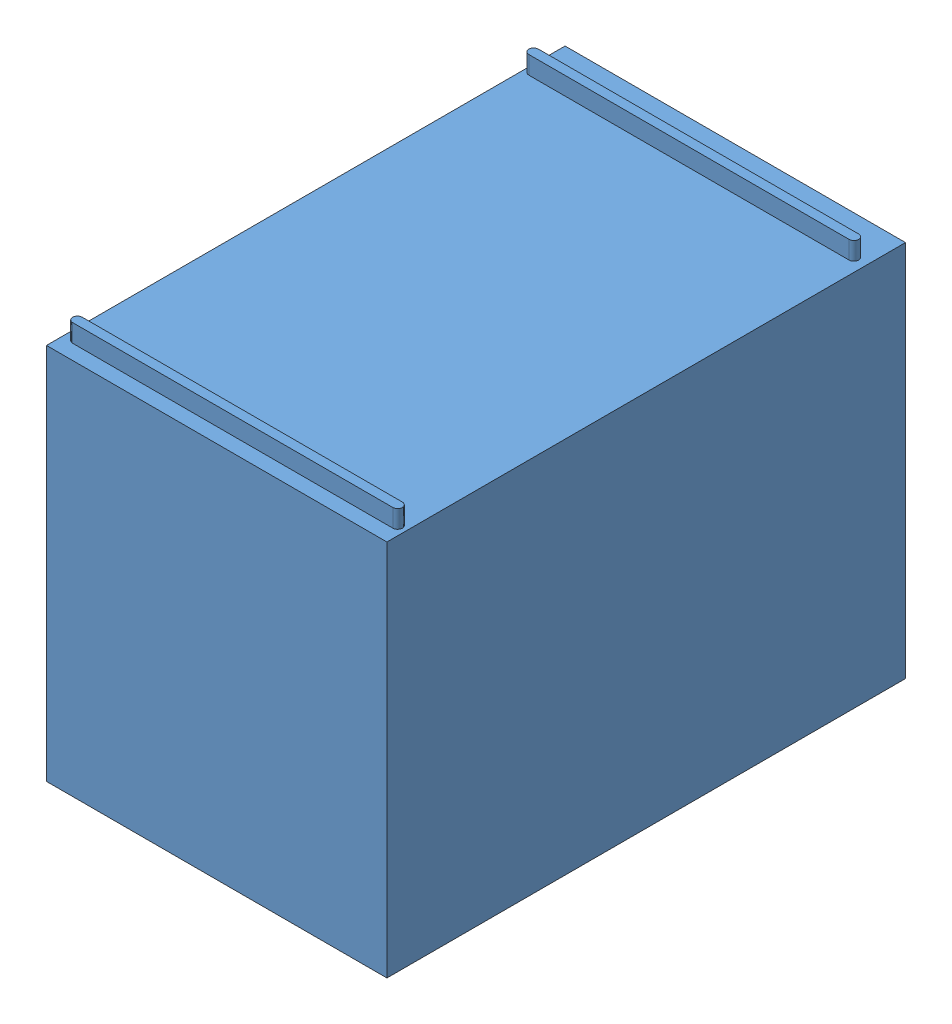
SolidWorks assembly ANA_GÖVDE, configuration Default. Lengths in mm.
Overall size (57 66.22 86.83).
200 component instances, 72 part files, 0 mates.
Components (placement in the parent):
- GÖVDE-1: GÖVDE [Default] at (-12.1036 34.1055 2.4795) size (57 66.22 86.83)
- ArduinoUno_CH340_USBC.step-1: ArduinoUno_CH340_USBC.step [Default] at (-8.7017 80.6973 66.2252) x (-0.00918 -0.026173 -0.999615) z (-0.017217 -0.999505 0.026328) size (73.95 53.67 14.6)
  - USB_C_Receptacle_16P_TopMnt_Horizontal_GCT_USB4105-xx-A036.step-1: USB_C_Receptacle_16P_TopMnt_Horizontal_GCT_USB4105-xx-A036.step [Default] at (-29.25 35.05 0) x (0 -1 0) z (0 0 1) size (8.94 7.78 4.26)
    - USB_C_Receptacle_16P_TopMnt_Horizontal_GCT_USB4105-xx-A.step-1: USB_C_Receptacle_16P_TopMnt_Horizontal_GCT_USB4105-xx-A.step [Default] at origin size (0.25 2.4 0.1)
    - USB_C_Receptacle_16P_TopMnt_Horizontal_GCT_USB4105-xx-A001.step-1: USB_C_Receptacle_16P_TopMnt_Horizontal_GCT_USB4105-xx-A001.step [Default] at origin size (0.25 2.4 0.1)
    - USB_C_Receptacle_16P_TopMnt_Horizontal_GCT_USB4105-xx-A002.step-1: USB_C_Receptacle_16P_TopMnt_Horizontal_GCT_USB4105-xx-A002.step [Default] at origin size (0.25 1.9 0.1)
    - USB_C_Receptacle_16P_TopMnt_Horizontal_GCT_USB4105-xx-A003.step-1: USB_C_Receptacle_16P_TopMnt_Horizontal_GCT_USB4105-xx-A003.step [Default] at origin size (0.25 1.9 0.1)
    - USB_C_Receptacle_16P_TopMnt_Horizontal_GCT_USB4105-xx-A004.step-1: USB_C_Receptacle_16P_TopMnt_Horizontal_GCT_USB4105-xx-A004.step [Default] at origin size (0.25 2.4 0.1)
    - USB_C_Receptacle_16P_TopMnt_Horizontal_GCT_USB4105-xx-A005.step-1: USB_C_Receptacle_16P_TopMnt_Horizontal_GCT_USB4105-xx-A005.step [Default] at origin size (0.25 2.4 0.1)
    - USB_C_Receptacle_16P_TopMnt_Horizontal_GCT_USB4105-xx-A006.step-1: USB_C_Receptacle_16P_TopMnt_Horizontal_GCT_USB4105-xx-A006.step [Default] at origin size (0.25 1.9 0.1)
    - USB_C_Receptacle_16P_TopMnt_Horizontal_GCT_USB4105-xx-A007.step-1: USB_C_Receptacle_16P_TopMnt_Horizontal_GCT_USB4105-xx-A007.step [Default] at origin size (0.25 1.9 0.1)
    - USB_C_Receptacle_16P_TopMnt_Horizontal_GCT_USB4105-xx-A008.step-1: USB_C_Receptacle_16P_TopMnt_Horizontal_GCT_USB4105-xx-A008.step [Default] at origin size (4.45 7.05 3.59)
    - USB_C_Receptacle_16P_TopMnt_Horizontal_GCT_USB4105-xx-A009.step-1: USB_C_Receptacle_16P_TopMnt_Horizontal_GCT_USB4105-xx-A009.step [Default] at origin size (0.2 0.8 0.12)
    - USB_C_Receptacle_16P_TopMnt_Horizontal_GCT_USB4105-xx-A010.step-1: USB_C_Receptacle_16P_TopMnt_Horizontal_GCT_USB4105-xx-A010.step [Default] at origin size (0.2 0.8 0.12)
    - USB_C_Receptacle_16P_TopMnt_Horizontal_GCT_USB4105-xx-A011.step-1: USB_C_Receptacle_16P_TopMnt_Horizontal_GCT_USB4105-xx-A011.step [Default] at origin size (0.2 0.8 0.12)
    - USB_C_Receptacle_16P_TopMnt_Horizontal_GCT_USB4105-xx-A012.step-1: USB_C_Receptacle_16P_TopMnt_Horizontal_GCT_USB4105-xx-A012.step [Default] at origin size (0.2 0.8 0.12)
    - USB_C_Receptacle_16P_TopMnt_Horizontal_GCT_USB4105-xx-A013.step-1: USB_C_Receptacle_16P_TopMnt_Horizontal_GCT_USB4105-xx-A013.step [Default] at origin size (0.2 0.8 0.12)
    - USB_C_Receptacle_16P_TopMnt_Horizontal_GCT_USB4105-xx-A014.step-1: USB_C_Receptacle_16P_TopMnt_Horizontal_GCT_USB4105-xx-A014.step [Default] at origin size (0.2 0.8 0.12)
    - USB_C_Receptacle_16P_TopMnt_Horizontal_GCT_USB4105-xx-A015.step-1: USB_C_Receptacle_16P_TopMnt_Horizontal_GCT_USB4105-xx-A015.step [Default] at origin size (0.2 0.8 0.12)
    - USB_C_Receptacle_16P_TopMnt_Horizontal_GCT_USB4105-xx-A016.step-1: USB_C_Receptacle_16P_TopMnt_Horizontal_GCT_USB4105-xx-A016.step [Default] at origin size (0.2 0.8 0.12)
    - USB_C_Receptacle_16P_TopMnt_Horizontal_GCT_USB4105-xx-A017.step-1: USB_C_Receptacle_16P_TopMnt_Horizontal_GCT_USB4105-xx-A017.step [Default] at origin size (4.47 7.33 4.26)
    - USB_C_Receptacle_16P_TopMnt_Horizontal_GCT_USB4105-xx-A018.step-1: USB_C_Receptacle_16P_TopMnt_Horizontal_GCT_USB4105-xx-A018.step [Default] at origin size (0.25 2.4 0.1)
    - USB_C_Receptacle_16P_TopMnt_Horizontal_GCT_USB4105-xx-A019.step-1: USB_C_Receptacle_16P_TopMnt_Horizontal_GCT_USB4105-xx-A019.step [Default] at origin size (0.25 2.4 0.1)
    - USB_C_Receptacle_16P_TopMnt_Horizontal_GCT_USB4105-xx-A020.step-1: USB_C_Receptacle_16P_TopMnt_Horizontal_GCT_USB4105-xx-A020.step [Default] at origin size (0.25 1.9 0.1)
    - USB_C_Receptacle_16P_TopMnt_Horizontal_GCT_USB4105-xx-A021.step-1: USB_C_Receptacle_16P_TopMnt_Horizontal_GCT_USB4105-xx-A021.step [Default] at origin size (0.25 1.9 0.1)
    - USB_C_Receptacle_16P_TopMnt_Horizontal_GCT_USB4105-xx-A022.step-1: USB_C_Receptacle_16P_TopMnt_Horizontal_GCT_USB4105-xx-A022.step [Default] at origin size (0.25 2.4 0.1)
    - USB_C_Receptacle_16P_TopMnt_Horizontal_GCT_USB4105-xx-A023.step-1: USB_C_Receptacle_16P_TopMnt_Horizontal_GCT_USB4105-xx-A023.step [Default] at origin size (0.25 2.4 0.1)
    - USB_C_Receptacle_16P_TopMnt_Horizontal_GCT_USB4105-xx-A024.step-1: USB_C_Receptacle_16P_TopMnt_Horizontal_GCT_USB4105-xx-A024.step [Default] at origin size (0.25 1.9 0.1)
    - USB_C_Receptacle_16P_TopMnt_Horizontal_GCT_USB4105-xx-A025.step-1: USB_C_Receptacle_16P_TopMnt_Horizontal_GCT_USB4105-xx-A025.step [Default] at origin size (0.25 1.9 0.1)
    - USB_C_Receptacle_16P_TopMnt_Horizontal_GCT_USB4105-xx-A026.step-1: USB_C_Receptacle_16P_TopMnt_Horizontal_GCT_USB4105-xx-A026.step [Default] at origin size (4.45 7.05 3.59)
    - USB_C_Receptacle_16P_TopMnt_Horizontal_GCT_USB4105-xx-A027.step-1: USB_C_Receptacle_16P_TopMnt_Horizontal_GCT_USB4105-xx-A027.step [Default] at origin size (0.2 0.8 0.12)
    - USB_C_Receptacle_16P_TopMnt_Horizontal_GCT_USB4105-xx-A028.step-1: USB_C_Receptacle_16P_TopMnt_Horizontal_GCT_USB4105-xx-A028.step [Default] at origin size (0.2 0.8 0.12)
    - USB_C_Receptacle_16P_TopMnt_Horizontal_GCT_USB4105-xx-A029.step-1: USB_C_Receptacle_16P_TopMnt_Horizontal_GCT_USB4105-xx-A029.step [Default] at origin size (0.2 0.8 0.12)
    - USB_C_Receptacle_16P_TopMnt_Horizontal_GCT_USB4105-xx-A030.step-1: USB_C_Receptacle_16P_TopMnt_Horizontal_GCT_USB4105-xx-A030.step [Default] at origin size (0.2 0.8 0.12)
    - USB_C_Receptacle_16P_TopMnt_Horizontal_GCT_USB4105-xx-A031.step-1: USB_C_Receptacle_16P_TopMnt_Horizontal_GCT_USB4105-xx-A031.step [Default] at origin size (0.2 0.8 0.12)
    - USB_C_Receptacle_16P_TopMnt_Horizontal_GCT_USB4105-xx-A032.step-1: USB_C_Receptacle_16P_TopMnt_Horizontal_GCT_USB4105-xx-A032.step [Default] at origin size (0.2 0.8 0.12)
    - USB_C_Receptacle_16P_TopMnt_Horizontal_GCT_USB4105-xx-A033.step-1: USB_C_Receptacle_16P_TopMnt_Horizontal_GCT_USB4105-xx-A033.step [Default] at origin size (0.2 0.8 0.12)
    - USB_C_Receptacle_16P_TopMnt_Horizontal_GCT_USB4105-xx-A034.step-1: USB_C_Receptacle_16P_TopMnt_Horizontal_GCT_USB4105-xx-A034.step [Default] at origin size (0.2 0.8 0.12)
    - USB_C_Receptacle_16P_TopMnt_Horizontal_GCT_USB4105-xx-A035.step-1: USB_C_Receptacle_16P_TopMnt_Horizontal_GCT_USB4105-xx-A035.step [Default] at origin size (4.47 7.33 4.26)
  - BarrelJack_Horizontal005.step-1: BarrelJack_Horizontal005.step [Default] at (-24.6 4.05 0) size (14.2 9.3 14.6)
    - BarrelJack_Horizontal.step-1: BarrelJack_Horizontal.step [Default] at origin size (13.7 9 10.8)
    - BarrelJack_Horizontal001.step-1: BarrelJack_Horizontal001.step [Default] at origin size (14.2 5.28 12.54)
    - BarrelJack_Horizontal002.step-1: BarrelJack_Horizontal002.step [Default] at origin size (10.5 5 3.6)
    - BarrelJack_Horizontal003.step-1: BarrelJack_Horizontal003.step [Default] at origin size (2 6.72 7.2)
    - BarrelJack_Horizontal004.step-1: BarrelJack_Horizontal004.step [Default] at origin size (0.2 2 3.8)
  - C_Elec_63x054_1.step-1: C_Elec_63x054_1.step [Default] at (-11.6 6.15 0) x (0 -1 0) z (0 0 1) size (8.61 8.6 5.4)
    - C_Elec_63x54.step-1: C_Elec_63x54.step [Default] at origin size (8.61 8.6 5.4)
    - C_Elec_63x055.step-1: C_Elec_63x055.step [Default] at origin size (0.02 0.02 0.01)
  - C_Elec_63x054_1.step-2: C_Elec_63x054_1.step [Default] at (-18.65 6.15 0) x (0 -1 0) z (0 0 1) size (8.61 8.6 5.4)
    - C_Elec_63x54.step-1: C_Elec_63x54.step [Default] at origin size (8.61 8.6 5.4)
    - C_Elec_63x055.step-1: C_Elec_63x055.step [Default] at origin size (0.02 0.02 0.01)
  - Resistors.step-1: Resistors.step [Default] at origin size (57.6 24.2 0.45)
    - R_0603_1608Metric.step-1: R_0603_1608Metric.step [Default] at (-30.35 41.6 0) size (1.6 0.8 0.45)
    - R_0603_1608Metric.step-2: R_0603_1608Metric.step [Default] at (-30.45 28.5 0) size (1.6 0.8 0.45)
    - R_0603_1608Metric.step-3: R_0603_1608Metric.step [Default] at (-30.15 24.3 0) size (1.6 0.8 0.45)
    - R_0603_1608Metric.step-4: R_0603_1608Metric.step [Default] at (-26.3 20.25 0) x (0 1 0) z (0 0 1) size (1.6 0.8 0.45)
    - R_0603_1608Metric.step-5: R_0603_1608Metric.step [Default] at (-23.85 20.3 0) x (0 1 0) z (0 0 1) size (1.6 0.8 0.45)
    - R_0603_1608Metric.step-6: R_0603_1608Metric.step [Default] at (-6.75 37.3 0) size (1.6 0.8 0.45)
    - R_0603_1608Metric.step-7: R_0603_1608Metric.step [Default] at (-6.8 35.35 0) size (1.6 0.8 0.45)
    - R_0603_1608Metric.step-8: R_0603_1608Metric.step [Default] at (-6.75 31 0) size (1.6 0.8 0.45)
    - R_0603_1608Metric.step-9: R_0603_1608Metric.step [Default] at (-6.8 28.85 0) size (1.6 0.8 0.45)
    - R_0603_1608Metric.step-10: R_0603_1608Metric.step [Default] at (-6.8 24.45 0) size (1.6 0.8 0.45)
    - R_0603_1608Metric.step-11: R_0603_1608Metric.step [Default] at (-6.85 18.2 0) size (1.6 0.8 0.45)
    - R_0603_1608Metric.step-12: R_0603_1608Metric.step [Default] at (23.75 26.5 0) x (0 1 0) z (0 0 1) size (1.6 0.8 0.45)
    - R_0603_1608Metric.step-13: R_0603_1608Metric.step [Default] at (25.95 25.65 0) x (0 1 0) z (0 0 1) size (1.6 0.8 0.45)
  - Capacitors.step-1: Capacitors.step [Default] at origin size (50.6 26.8 0.8)
    - C_0603_1608Metric.step-1: C_0603_1608Metric.step [Default] at (-20.2 39.55 0) size (1.6 0.8 0.8)
    - C_0603_1608Metric.step-2: C_0603_1608Metric.step [Default] at (-16.1 39.55 0) size (1.6 0.8 0.8)
    - C_0603_1608Metric.step-3: C_0603_1608Metric.step [Default] at (-11.95 39.55 0) size (1.6 0.8 0.8)
    - C_0603_1608Metric.step-4: C_0603_1608Metric.step [Default] at (-25.6 26.45 0) size (1.6 0.8 0.8)
    - C_0603_1608Metric.step-5: C_0603_1608Metric.step [Default] at (-25.65 24.35 0) size (1.6 0.8 0.8)
    - C_0603_1608Metric.step-6: C_0603_1608Metric.step [Default] at (-6.85 22.4 0) size (1.6 0.8 0.8)
    - C_0603_1608Metric.step-7: C_0603_1608Metric.step [Default] at (-17.65 17.95 0) size (1.6 0.8 0.8)
    - C_0603_1608Metric.step-8: C_0603_1608Metric.step [Default] at (-11.9 18 0) size (1.6 0.8 0.8)
    - C_0603_1608Metric.step-9: C_0603_1608Metric.step [Default] at (-22.85 14 0) x (0 1 0) z (0 0 1) size (1.6 0.8 0.8)
    - C_0603_1608Metric.step-10: C_0603_1608Metric.step [Default] at (-15.6 13.95 0) x (0 1 0) z (0 0 1) size (1.6 0.8 0.8)
    - C_0603_1608Metric.step-11: C_0603_1608Metric.step [Default] at (23.75 30.55 0) x (0 1 0) z (0 0 1) size (1.6 0.8 0.8)
    - C_0603_1608Metric.step-12: C_0603_1608Metric.step [Default] at (23.75 22.5 0) x (0 1 0) z (0 0 1) size (1.6 0.8 0.8)
  - Array.step-1: Array.step [Default] at origin size (19.58 4.34 1.7)
    - trou001.step-1: trou001.step [Default] at (-5.08 0 0) size (1.8 1.8 1.7)
    - trou001.step-2: trou001.step [Default] at (-5.08 2.54 0) size (1.8 1.8 1.7)
    - trou001.step-3: trou001.step [Default] at (-2.54 0 0) size (1.8 1.8 1.7)
    - trou001.step-4: trou001.step [Default] at (-2.54 2.54 0) size (1.8 1.8 1.7)
    - trou001.step-5: trou001.step [Default] at origin size (1.8 1.8 1.7)
    - trou001.step-6: trou001.step [Default] at (0 2.54 0) size (1.8 1.8 1.7)
    - trou001.step-7: trou001.step [Default] at (2.54 0 0) size (1.8 1.8 1.7)
    - trou001.step-8: trou001.step [Default] at (2.54 2.54 0) size (1.8 1.8 1.7)
    - trou001.step-9: trou001.step [Default] at (5.08 0 0) size (1.8 1.8 1.7)
    - trou001.step-10: trou001.step [Default] at (5.08 2.54 0) size (1.8 1.8 1.7)
    - trou001.step-11: trou001.step [Default] at (7.62 0 0) size (1.8 1.8 1.7)
    - trou001.step-12: trou001.step [Default] at (7.62 2.54 0) size (1.8 1.8 1.7)
    - trou001.step-13: trou001.step [Default] at (10.16 0 0) size (1.8 1.8 1.7)
    - trou001.step-14: trou001.step [Default] at (10.16 2.54 0) size (1.8 1.8 1.7)
    - trou001.step-15: trou001.step [Default] at (12.7 0 0) size (1.8 1.8 1.7)
    - trou001.step-16: trou001.step [Default] at (12.7 2.54 0) size (1.8 1.8 1.7)
  - Array001.step-1: Array001.step [Default] at origin size (14.5 4.34 1.7)
    - trou002.step-1: trou002.step [Default] at (17.78 0 0) size (1.8 1.8 1.7)
    - trou002.step-2: trou002.step [Default] at (17.78 2.54 0) size (1.8 1.8 1.7)
    - trou002.step-3: trou002.step [Default] at (20.32 0 0) size (1.8 1.8 1.7)
    - trou002.step-4: trou002.step [Default] at (20.32 2.54 0) size (1.8 1.8 1.7)
    - trou002.step-5: trou002.step [Default] at (22.86 0 0) size (1.8 1.8 1.7)
    - trou002.step-6: trou002.step [Default] at (22.86 2.54 0) size (1.8 1.8 1.7)
    - trou002.step-7: trou002.step [Default] at (25.4 0 0) size (1.8 1.8 1.7)
    - trou002.step-8: trou002.step [Default] at (25.4 2.54 0) size (1.8 1.8 1.7)
    - trou002.step-9: trou002.step [Default] at (27.94 0 0) size (1.8 1.8 1.7)
    - trou002.step-10: trou002.step [Default] at (27.94 2.54 0) size (1.8 1.8 1.7)
    - trou002.step-11: trou002.step [Default] at (30.48 0 0) size (1.8 1.8 1.7)
    - trou002.step-12: trou002.step [Default] at (30.48 2.54 0) size (1.8 1.8 1.7)
  - Array002.step-1: Array002.step [Default] at origin size (24.66 4.34 1.7)
    - trou003.step-1: trou003.step [Default] at (-13.97 45.72 0) size (1.8 1.8 1.7)
    - trou003.step-2: trou003.step [Default] at (-13.97 48.26 0) size (1.8 1.8 1.7)
    - trou003.step-3: trou003.step [Default] at (-11.43 45.72 0) size (1.8 1.8 1.7)
    - trou003.step-4: trou003.step [Default] at (-11.43 48.26 0) size (1.8 1.8 1.7)
    - trou003.step-5: trou003.step [Default] at (-8.89 45.72 0) size (1.8 1.8 1.7)
    - trou003.step-6: trou003.step [Default] at (-8.89 48.26 0) size (1.8 1.8 1.7)
    - trou003.step-7: trou003.step [Default] at (-6.35 45.72 0) size (1.8 1.8 1.7)
    - trou003.step-8: trou003.step [Default] at (-6.35 48.26 0) size (1.8 1.8 1.7)
    - trou003.step-9: trou003.step [Default] at (-3.81 45.72 0) size (1.8 1.8 1.7)
    - trou003.step-10: trou003.step [Default] at (-3.81 48.26 0) size (1.8 1.8 1.7)
    - trou003.step-11: trou003.step [Default] at (-1.27 45.72 0) size (1.8 1.8 1.7)
    - trou003.step-12: trou003.step [Default] at (-1.27 48.26 0) size (1.8 1.8 1.7)
    - trou003.step-13: trou003.step [Default] at (1.27 45.72 0) size (1.8 1.8 1.7)
    - trou003.step-14: trou003.step [Default] at (1.27 48.26 0) size (1.8 1.8 1.7)
    - trou003.step-15: trou003.step [Default] at (3.81 45.72 0) size (1.8 1.8 1.7)
    - trou003.step-16: trou003.step [Default] at (3.81 48.26 0) size (1.8 1.8 1.7)
    - trou003.step-17: trou003.step [Default] at (6.35 45.72 0) size (1.8 1.8 1.7)
    - trou003.step-18: trou003.step [Default] at (6.35 48.26 0) size (1.8 1.8 1.7)
    - trou003.step-19: trou003.step [Default] at (8.89 45.72 0) size (1.8 1.8 1.7)
    - trou003.step-20: trou003.step [Default] at (8.89 48.26 0) size (1.8 1.8 1.7)
  - Array003.step-1: Array003.step [Default] at origin size (19.58 4.34 1.7)
    - trou004.step-1: trou004.step [Default] at (12.7 45.72 0) size (1.8 1.8 1.7)
    - trou004.step-2: trou004.step [Default] at (12.7 48.26 0) size (1.8 1.8 1.7)
    - trou004.step-3: trou004.step [Default] at (15.24 45.72 0) size (1.8 1.8 1.7)
    - trou004.step-4: trou004.step [Default] at (15.24 48.26 0) size (1.8 1.8 1.7)
    - trou004.step-5: trou004.step [Default] at (17.78 45.72 0) size (1.8 1.8 1.7)
    - trou004.step-6: trou004.step [Default] at (17.78 48.26 0) size (1.8 1.8 1.7)
    - trou004.step-7: trou004.step [Default] at (20.32 45.72 0) size (1.8 1.8 1.7)
    - trou004.step-8: trou004.step [Default] at (20.32 48.26 0) size (1.8 1.8 1.7)
    - trou004.step-9: trou004.step [Default] at (22.86 45.72 0) size (1.8 1.8 1.7)
    - trou004.step-10: trou004.step [Default] at (22.86 48.26 0) size (1.8 1.8 1.7)
    - trou004.step-11: trou004.step [Default] at (25.4 45.72 0) size (1.8 1.8 1.7)
    - trou004.step-12: trou004.step [Default] at (25.4 48.26 0) size (1.8 1.8 1.7)
    - trou004.step-13: trou004.step [Default] at (27.94 45.72 0) size (1.8 1.8 1.7)
    - trou004.step-14: trou004.step [Default] at (27.94 48.26 0) size (1.8 1.8 1.7)
    - trou004.step-15: trou004.step [Default] at (30.48 45.72 0) size (1.8 1.8 1.7)
    - trou004.step-16: trou004.step [Default] at (30.48 48.26 0) size (1.8 1.8 1.7)
  - Array004.step-1: Array004.step [Default] at origin size (4.34 6.88 1.7)
    - trou005.step-1: trou005.step [Default] at (30.52 22.62 0) size (1.8 1.8 1.7)
    - trou005.step-2: trou005.step [Default] at (30.52 25.16 0) size (1.8 1.8 1.7)
    - trou005.step-3: trou005.step [Default] at (30.52 27.7 0) size (1.8 1.8 1.7)
    - trou005.step-4: trou005.step [Default] at (33.06 22.62 0) size (1.8 1.8 1.7)
    - trou005.step-5: trou005.step [Default] at (33.06 25.16 0) size (1.8 1.8 1.7)
    - trou005.step-6: trou005.step [Default] at (33.06 27.7 0) size (1.8 1.8 1.7)
  - Groupe.step-1: Groupe.step [Default] at origin size (9.42 1.8 1.7)
    - Array005.step-1: Array005.step [Default] at origin size (6.88 1.8 1.7)
      - trou007.step-1: trou007.step [Default] at (-17.71 21.05 0) size (1.8 1.8 1.7)
      - trou007.step-2: trou007.step [Default] at (-15.17 21.05 0) size (1.8 1.8 1.7)
      - trou007.step-3: trou007.step [Default] at (-12.63 21.05 0) size (1.8 1.8 1.7)
    - trou006.step-1: trou006.step [Default] at (-20.25 21.05 0) size (1.8 1.8 1.7)
  - Groupe-1.step-1: Groupe-1.step [Default] at (45.75 -7.95 0) size (9.42 1.8 1.7)
    - Array005.step-1: Array005.step [Default] at origin size (6.88 1.8 1.7)
      - trou007.step-1: trou007.step [Default] at (-17.71 21.05 0) size (1.8 1.8 1.7)
      - trou007.step-2: trou007.step [Default] at (-15.17 21.05 0) size (1.8 1.8 1.7)
      - trou007.step-3: trou007.step [Default] at (-12.63 21.05 0) size (1.8 1.8 1.7)
    - trou006.step-1: trou006.step [Default] at (-20.25 21.05 0) size (1.8 1.8 1.7)
  - Groupe-2.step-1: Groupe-2.step [Default] at (45.75 -5.25 0) size (9.42 1.8 1.7)
    - Array005.step-1: Array005.step [Default] at origin size (6.88 1.8 1.7)
      - trou007.step-1: trou007.step [Default] at (-17.71 21.05 0) size (1.8 1.8 1.7)
      - trou007.step-2: trou007.step [Default] at (-15.17 21.05 0) size (1.8 1.8 1.7)
      - trou007.step-3: trou007.step [Default] at (-12.63 21.05 0) size (1.8 1.8 1.7)
    - trou006.step-1: trou006.step [Default] at (-20.25 21.05 0) size (1.8 1.8 1.7)
  - Groupe002.step-1: Groupe002.step [Default] at (45.75 -2.6 0) size (9.42 1.8 1.7)
    - Array005.step-1: Array005.step [Default] at origin size (6.88 1.8 1.7)
      - trou007.step-1: trou007.step [Default] at (-17.71 21.05 0) size (1.8 1.8 1.7)
      - trou007.step-2: trou007.step [Default] at (-15.17 21.05 0) size (1.8 1.8 1.7)
      - trou007.step-3: trou007.step [Default] at (-12.63 21.05 0) size (1.8 1.8 1.7)
    - trou006.step-1: trou006.step [Default] at (-20.25 21.05 0) size (1.8 1.8 1.7)
  - Corps.step-1: Corps.step [Default] at origin size (68.6 53.67 1.6)
  - LQFP_32_7x7mm_P08mm.step-1: LQFP_32_7x7mm_P08mm.step [Default] at (8.8 23.8 0) x (-1 0 0) z (0 0 1) size (9 9 1.5)
  - Crystal_SMD_HC49-SD.step-1: Crystal_SMD_HC49-SD.step [Default] at (19.85 24.95 0) x (0 -1 0) z (0 0 1) size (12.5 4.65 4)
  - Crystal_SMD_HC49-SD001.step-1: Crystal_SMD_HC49-SD001.step [Default] at (-15.75 35.75 0) size (12.5 4.65 4)
  - SOIC_16_39x99mm_P127mm.step-1: SOIC_16_39x99mm_P127mm.step [Default] at (-16.5 27.7 0) x (0 -1 0) z (0 0 1) size (6 9.9 1.75)
  - SOIC_8_1EP_39x49mm_P127mm.step-1: SOIC_8_1EP_39x49mm_P127mm.step [Default] at (-9.55 14.05 0) size (6 4.9 1.75)
  - SOT_23_1.step-1: SOT_23_1.step [Default] at (-19 13.7 0) x (-1 0 0) z (0 0 1) size (2.5 3 1.2)
  - SOT_223.step-1: SOT_223.step [Default] at (-28.95 14 0) x (-1 0 0) z (0 0 1) size (7 6.5 1.7)
  - SOT_23_2.step-1: SOT_23_2.step [Default] at (-29.55 21.25 0) x (-1 0 0) z (0 0 1) size (2.5 3 1.2)
  - RedButton.step-1: RedButton.step [Default] at (-39.9125 53.9663 0.0304) size (8.4 6.2 3)
  - PinHeader_2x03_P254mm_Vertical.step-1: PinHeader_2x03_P254mm_Vertical.step [Default] at (30.55 27.7 0) size (5.08 7.62 11.54)
  - PinSocket_1x08_P2.54mm_Vertical.step-1: PinSocket_1x08_P2.54mm_Vertical.step [Default] at (30.5 48.25 0) x (0 -1 0) z (0 0 1) size (2.54 20.32 11.6)
  - PinSocket_1x06_P2.54mm_Vertical.step-1: PinSocket_1x06_P2.54mm_Vertical.step [Default] at (30.45 0 0) x (0 -1 0) z (0 0 1) size (2.54 15.24 11.6)
  - PinSocket_1x08_P2.54mm_Vertical.step-2: PinSocket_1x08_P2.54mm_Vertical.step [Default] at (12.7 0 0) x (0 -1 0) z (0 0 1) size (2.54 20.32 11.6)
  - PinSocket_1x10_P2.54mm_Vertical.step-1: PinSocket_1x10_P2.54mm_Vertical.step [Default] at (8.9 48.25 0) x (0 -1 0) z (0 0 1) size (2.54 25.4 11.6)
  - D_SMA.step-1: D_SMA.step [Default] at (-11.75 -0.45 0) x (-1 0 0) z (0 0 1) size (5 2.7 2.22)
  - D_SOD_123.step-1: D_SOD_123.step [Default] at (27.85 25.8 0) x (0 -1 0) z (0 0 1) size (3.8 1.6 1.25)
  - LED_0603_1608Metric_ON.step-1: LED_0603_1608Metric_ON.step [Default] at (-6.75 39.4 0) size (1.6 0.8 1.1)
  - LED_0603_1608Metric_ON.step-2: LED_0603_1608Metric_ON.step [Default] at (-6.75 33.1 0) size (1.6 0.8 1.1)
  - LED_0603_1608Metric_ON.step-3: LED_0603_1608Metric_ON.step [Default] at (-6.8 26.65 0) size (1.6 0.8 1.1)
  - LED_0603_1608Metric_ON.step-4: LED_0603_1608Metric_ON.step [Default] at (-6.85 20.25 0) size (1.6 0.8 1.1)
  - Text_UNO.step-1: Text_UNO.step [Default] at (2.35 32.9 0) size (13.67 4.84 0.05)
- ST7735.step-1: ST7735.step [Default] at (-5.0665 48.2404 79.8206) x (0.007365 0.001454 0.999972) z (-0.999896 0.012416 0.007346) size (54 45 13.3)
